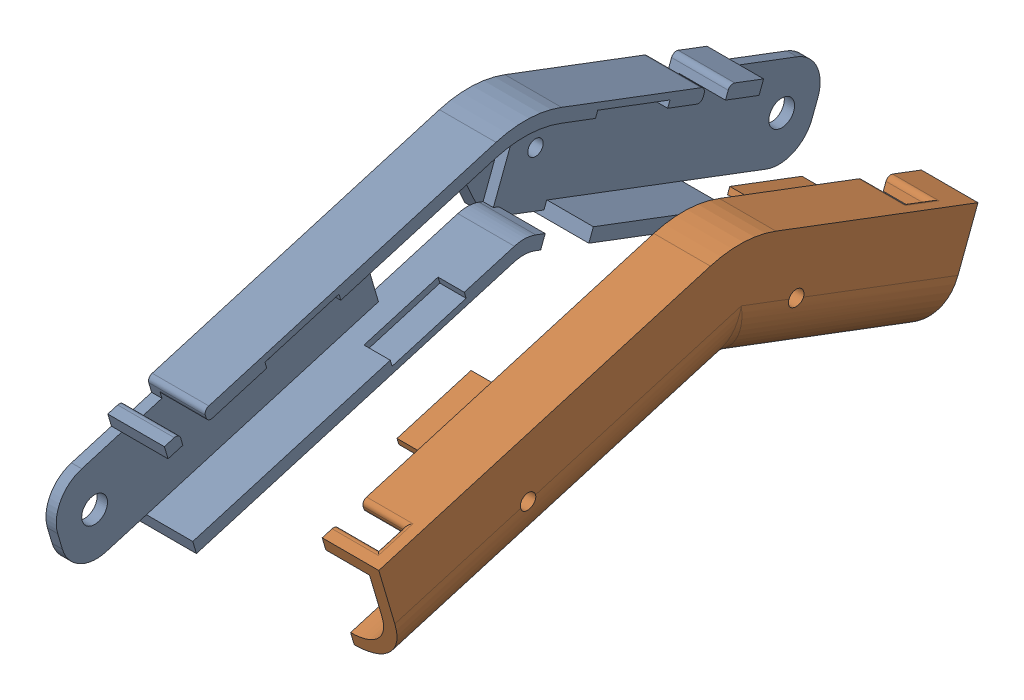
SolidWorks assembly Wire Holder Assembly, configuration Default. Lengths in mm.
Overall size (55.74 41.09 148.41).
2 component instances, 2 part files, 3 mates.
Components (placement in the parent):
- Linkage Arm Wire Holder (Bottom Part)-1: Linkage Arm Wire Holder (Bottom Part) [Default] at origin size (14 41.09 148.41)
- Linkage Arm Wire Holder (Top Part)-1: Linkage Arm Wire Holder (Top Part) [Default] at (30.6553 0 0) size (16.09 40.92 116.42)
Mates (geometry in assembly coordinates):
- Coincident1: coincident aligned: plane of Linkage Arm Wire Holder (Bottom Part)-1 through (0 16.203 -127.0924) normal (0 -0.353627 -0.935386); plane of Linkage Arm Wire Holder (Top Part)-1 through (30.6553 16.203 -127.0924) normal (0 -0.353627 -0.935386)
- Coincident2: coincident: plane of Linkage Arm Wire Holder (Bottom Part)-1 through (0 0 0) normal (1 0 0); plane of Linkage Arm Wire Holder (Top Part)-1 through (0 0 0) normal (-1 0 0)
- Coincident3: coincident aligned: plane of Linkage Arm Wire Holder (Bottom Part)-1 through (-11 26.4922 -130.9823) normal (0 0.935386 -0.353627); plane of Linkage Arm Wire Holder (Top Part)-1 through (19.6553 26.4922 -130.9823) normal (0 0.935386 -0.353627)
